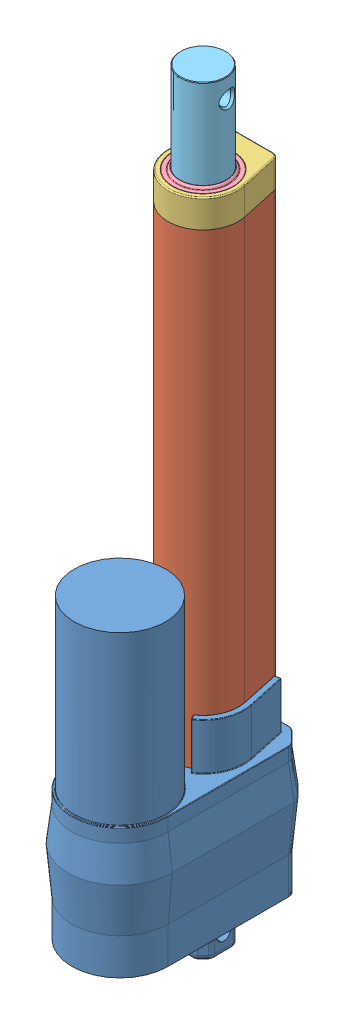
SolidWorks assembly HDA-6-2, configuration Default. Lengths in mm.
Overall size (45.73 331.55 84.91).
5 component instances, 5 part files, 10 mates.
Components (placement in the parent):
- HDA-BASE-1: HDA-BASE [Default] at origin size (45.73 149.35 84.91)
- HDA-SHROUD-1: HDA-SHROUD [6IN] at (0 56.642 0) size (30.48 203.2 36.83)
- HDA-SHROUD-CAP-2: HDA-SHROUD-CAP [Default] at (0 259.842 0) size (30.48 12.19 36.83)
- HDA-CAP-SEAL-1: HDA-CAP-SEAL [Default] at (0 269.494 0) size (26.42 3.52 26.42)
- HDA-STROKE-1: HDA-STROKE [6IN] at (0 311.6135 0) x (0.146185 0 0.989257) z (0.989257 0 -0.146185) size (19.94 170.18 20.14)
Mates (geometry in assembly coordinates):
- Coincident1: coincident anti-aligned: plane of HDA-BASE-1 through (0 56.642 36.195) normal (0 1 0); plane of HDA-SHROUD-1 through (0 56.642 0) normal (0 -1 0)
- Concentric1: concentric aligned: cylinder of HDA-BASE-1 through (0 76.962 0) axis (0 -1 0) radius 15.24; cylinder of HDA-SHROUD-1 through (0 107.442 0) axis (0 -1 0) radius 15.24
- Coincident2: coincident anti-aligned: plane of HDA-SHROUD-CAP-2 through (0 259.842 0) normal (0 -1 0); plane of HDA-SHROUD-1 through (8.8727 259.842 -19.05) normal (0 1 0)
- Concentric2: concentric aligned: cylinder of HDA-SHROUD-1 through (0 107.442 0) axis (0 -1 0) radius 15.24; cylinder of HDA-SHROUD-CAP-2 through (0 272.034 0) axis (0 -1 0) radius 15.24
- Coincident3: coincident anti-aligned: plane of HDA-SHROUD-CAP-2 through (0 269.494 0) normal (0 1 0); plane of HDA-CAP-SEAL-1 through (-13.208 269.494 0) normal (0 -1 0)
- Concentric4: concentric anti-aligned: cylinder of HDA-SHROUD-CAP-2 through (0 269.494 0) axis (0 1 0) radius 13.208; cylinder of HDA-CAP-SEAL-1 through (0 269.494 0) axis (0 -1 0) radius 13.208
- Concentric5: concentric aligned: cylinder of HDA-STROKE-1 through (0 293.8335 0) axis (0 1 0) radius 9.9695; cylinder of HDA-SHROUD-CAP-2 through (0 259.842 0) axis (0 1 0) radius 9.9695
- LimitDistance1: limit distance = 39.5795 mm aligned: plane of HDA-STROKE-1 through (0 311.6135 0) normal (0 1 0); plane of HDA-SHROUD-CAP-2 through (0 272.034 0) normal (0 1 0)
- Coincident5: coincident aligned: plane of HDA-SHROUD-1 through (-10.922 107.442 -21.59) normal (0 0 -1); plane of HDA-SHROUD-CAP-2 through (-10.922 272.034 -21.59) normal (0 0 -1)
- Parallel3: parallel aligned: plane of HDA-BASE-1 through (-14.605 56.642 -24.13) normal (0 0 -1); plane of HDA-SHROUD-1 through (-10.922 107.442 -21.59) normal (0 0 -1)
